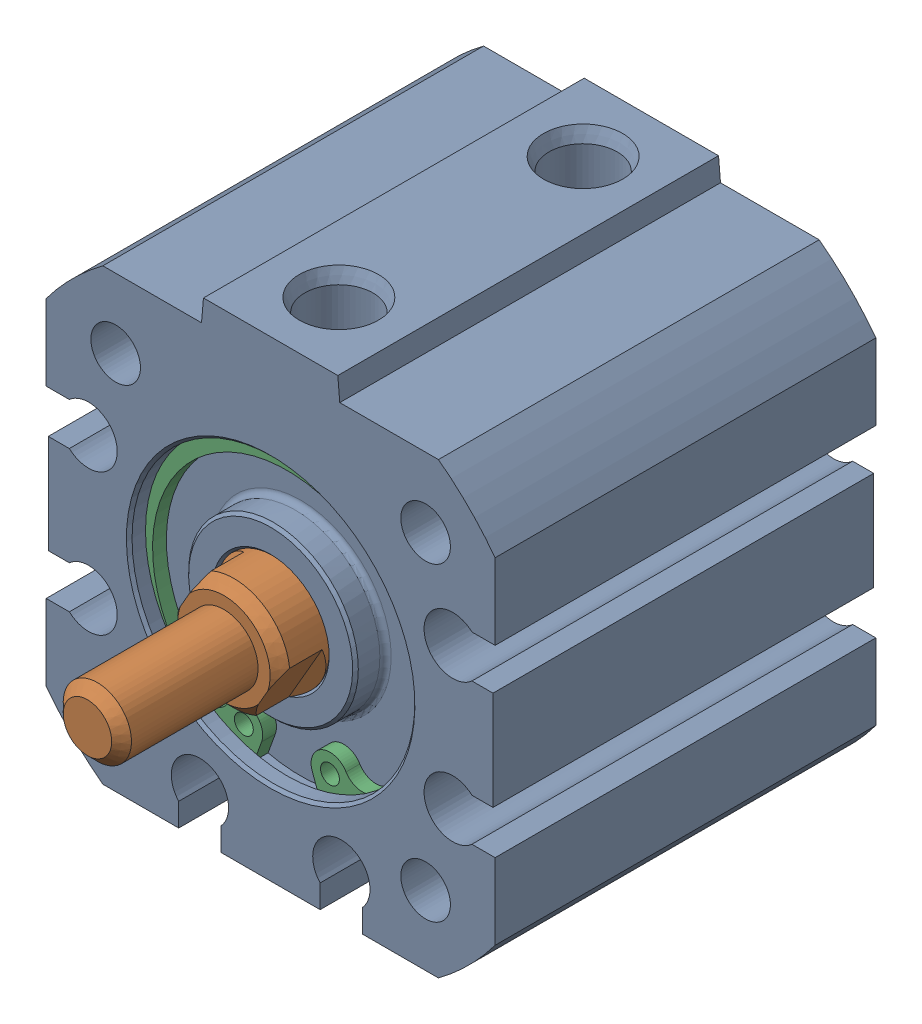
SolidWorks assembly 217-2778-001 Rev2_NCQ8A075-050M, configuration Default. Lengths in mm.
Overall size (31.75 33.34 39.88).
3 component instances, 3 part files, 0 mates.
Components (placement in the parent):
- 217-2778-NCQ8A075-050M_NCQ8 Tube_075A-1: 217-2778-NCQ8A075-050M_NCQ8 Tube_075A [Default] at origin size (31.75 33.34 26.92)
- 217-2778-NCQ8A075-050M_NCQ8 Rod_075M-1: 217-2778-NCQ8A075-050M_NCQ8 Rod_075M [Default] at (0 0 -8.85) x (0.866025 -0.5 0) z (0 0 1) size (18.95 18.95 35.27)
- 217-2778-NCQ8A075-050M_Snap Ring_075-1: 217-2778-NCQ8A075-050M_Snap Ring_075 [Default] at (0 0 10.362) size (21 20.74 0.97)
